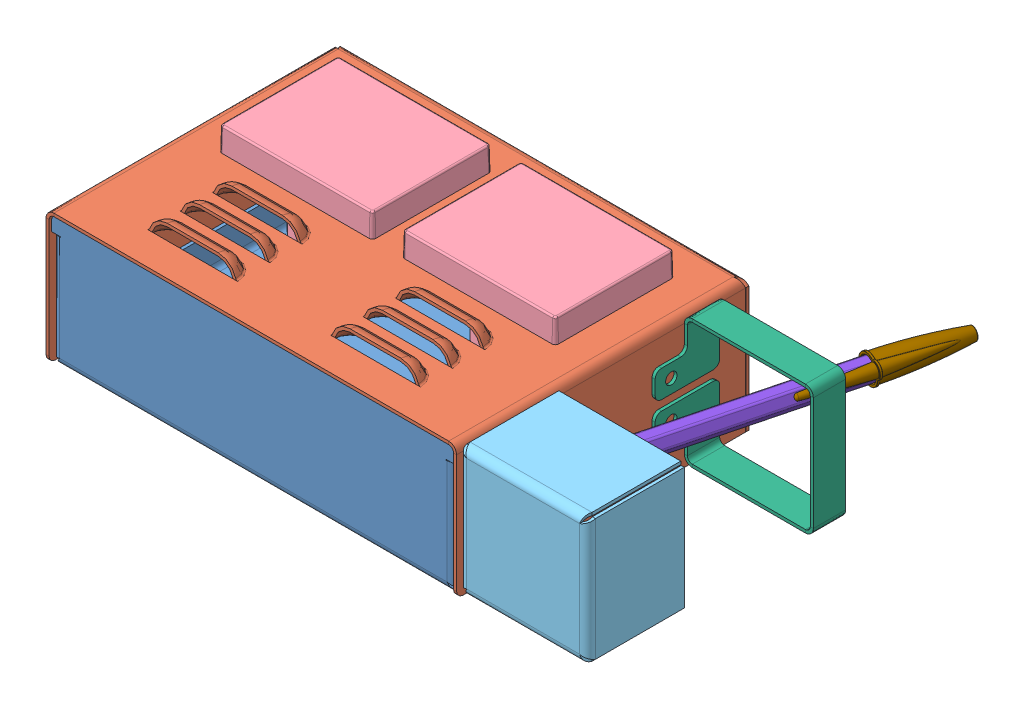
SolidWorks assembly L-Shape Assembly, configuration Default. Lengths in mm.
Overall size (225.75 61.58 154.1).
20 component instances, 13 part files, 25 mates.
Components (placement in the parent):
- Base-1: Base [Default] at origin size (158.76 50.8 112.83)
- Cover-1: Cover [Default] at (-80.8482 51.054 0.762) size (161.99 58.27 115.07)
- S-632-1 ZI-10: S-632-1 ZI [PEM S-632-1 ZI--N] at (-78.1558 28.575 -8.255) x (0 -1 0) z (0 0 1) size (7.11 2.74 7.11)
- S-632-1 ZI-11: S-632-1 ZI [PEM S-632-1 ZI--N] at (-78.1558 8.255 -20.955) x (0 -1 0) z (0 0 1) size (7.11 2.74 7.11)
- S-632-1 ZI-13: S-632-1 ZI [PEM S-632-1 ZI--N] at (-78.1558 8.255 -107.1118) x (0 -1 0) z (0 0 1) size (7.11 2.74 7.11)
- S-632-1 ZI-1: S-632-1 ZI [PEM S-440-1 ZI--N] at (78.1558 28.575 -8.255) x (0 1 0) z (0 0 1) size (6.35 2.74 6.35)
- S-632-1 ZI-4: S-632-1 ZI [PEM S-440-1 ZI--N] at (78.1558 8.255 -20.955) x (0 1 0) z (0 0 1) size (6.35 2.74 6.35)
- S-632-1 ZI-5: S-632-1 ZI [PEM S-440-1 ZI--N] at (78.1558 8.255 -107.1118) x (0 1 0) z (0 0 1) size (6.35 2.74 6.35)
- Jameco 316603-1: Jameco 316603 [Default] at (-35.9913 52.2732 -76.1931) x (1 0 0) z (0 1 0) size (60.5 47 37.3)
- Jameco 316603-2: Jameco 316603 [Default] at (35.9913 52.2732 -76.1931) x (1 0 0) z (0 1 0) size (60.5 47 37.3)
- Pencil Bottom-1: Pencil Bottom [Default] at (131.6482 52.2732 -1.2192) x (-1 0 0) z (0 0 1) size (50.8 50.8 50.8)
- Pencil Top-1: Pencil Top [Default] at (130.429 52.2732 -88.9) x (0 -1 0) z (1 0 0) size (50.8 25.4 50.8)
- BIC Pen Assembly Blue-1: BIC Pen Assembly Blue [Default] at (121.0447 61.6791 -89.1579) x (0.264397 0.013512 -0.964319) z (0.557576 0.813709 0.164278) size (148.8 15.39 16.22)
  - Nib-1: Nib [Default] at (57.1345 -8.7544 -20.0258) x (1 0 0) z (0 0.001361 0.999999) size (15.6 3.6 3.6)
  - Body-1: Body [Default] at (49.2214 -8.7544 -20.0258) size (134 7.6 8.57)
  - Pen Cap (Blue)-1: Pen Cap (Blue) [Default] at (28.2214 -8.7544 -20.0258) x (-1 0 0) z (0 0.890697 0.454597) size (60 12.7 10.8)
  - Nib Shroud-1: Nib Shroud [Default] at (54.7214 -8.7544 -20.0258) x (1 0 0) z (0 -0.048991 0.998799) size (14.5 5.4 5.4)
  - Nib Roller Ball-1: Nib Roller Ball [Default] at (57.1345 -8.7544 -20.0258) size (1.59 1.59 1.59)
  - End Cap (Blue)-1: End Cap (Blue) [Default] at (-79.2786 -8.7544 -20.0258) size (7.3 7.4 7.4)
  - Ink Tube-Vessel (Blue)-1: Ink Tube-Vessel (Blue) [Default] at (48.0214 -8.7544 -20.0258) size (120 2.96 2.96)
Mates (geometry in assembly coordinates):
- Distance4: distance = 0.254 mm anti-aligned: plane of Base-1; plane of Cover-1 through (207.2276 51.054 0.762) normal (0 -1 0)
- Distance6: distance = 0.762 mm aligned: plane of Base-1; plane of Cover-1
- Concentric71: concentric aligned: cylinder of Base-1 through (-79.375 8.255 -20.955) axis (1 0 0) radius 2.3876; cylinder of S-632-1 ZI-4 through (78.1558 8.255 -20.955) axis (1 0 0) radius 3.175
- Coincident141: coincident anti-aligned: plane of Base-1 through (78.1558 1.2192 -15.24) normal (-1 0 0); plane of S-632-1 ZI-4 through (78.1558 10.1276 -20.955) normal (1 0 0)
- Concentric81: concentric aligned: cylinder of Base-1 through (-79.375 8.255 -107.1118) axis (1 0 0) radius 2.3876; cylinder of S-632-1 ZI-5 through (78.1558 8.255 -107.1118) axis (1 0 0) radius 3.175
- Coincident151: coincident anti-aligned: plane of Base-1 through (78.1558 1.2192 -15.24) normal (-1 0 0); plane of S-632-1 ZI-5 through (78.1558 10.1276 -107.1118) normal (1 0 0)
- Concentric831: concentric aligned: cylinder of Base-1 through (-79.375 28.575 -8.255) axis (1 0 0) radius 2.3876; cylinder of S-632-1 ZI-1 through (78.1558 28.575 -8.255) axis (1 0 0) radius 3.175
- Coincident1531: coincident anti-aligned: plane of S-632-1 ZI-1 through (78.1558 30.4476 -8.255) normal (1 0 0); plane of Base-1 through (78.1558 3.1242 -1.2192) normal (-1 0 0)
- Distance7: distance = 0.254 mm anti-aligned: plane of Cover-1 through (-79.629 51.054 -111.1758) normal (1 0 0); plane of Base-1 through (-79.375 13.97 -15.24) normal (-1 0 0)
- Concentric83421: concentric anti-aligned: cylinder of Base-1 through (-79.375 28.575 -8.255) axis (1 0 0) radius 2.3876; cylinder of S-632-1 ZI-10 through (-78.1558 28.575 -8.255) axis (-1 0 0) radius 3.556
- Coincident153621: coincident anti-aligned: plane of Base-1 through (-78.1558 3.1242 -13.97) normal (1 0 0); plane of S-632-1 ZI-10 through (-78.1558 26.423 -8.255) normal (-1 0 0)
- Concentric83431: concentric anti-aligned: cylinder of Base-1 through (-79.375 8.255 -20.955) axis (1 0 0) radius 2.3876; cylinder of S-632-1 ZI-11 through (-78.1558 8.255 -20.955) axis (-1 0 0) radius 3.556
- Coincident153631: coincident anti-aligned: plane of Base-1 through (-78.1558 13.97 -15.24) normal (1 0 0); plane of S-632-1 ZI-11 through (-78.1558 6.103 -20.955) normal (-1 0 0)
- Concentric83451: concentric anti-aligned: cylinder of Base-1 through (-79.375 8.255 -107.1118) axis (1 0 0) radius 2.3876; cylinder of S-632-1 ZI-13 through (-78.1558 8.255 -107.1118) axis (-1 0 0) radius 3.556
- Coincident153651: coincident anti-aligned: plane of Base-1 through (-78.1558 13.97 -15.24) normal (1 0 0); plane of S-632-1 ZI-13 through (-78.1558 6.103 -107.1118) normal (-1 0 0)
- Concentric83453: concentric aligned: cylinder of Cover-1 through (35.9913 0 -76.1931) axis (0 1 0) radius 19.25; cylinder of Jameco 316603-2 through (35.9913 28.2732 -76.1931) axis (0 1 0) radius 19
- Coincident153652: coincident anti-aligned: plane of Cover-1 through (207.2276 52.2732 0.762) normal (0 1 0); plane of Jameco 316603-2 through (35.9913 52.2732 -76.1931) normal (0 -1 0)
- Coincident153653: coincident anti-aligned: plane of Cover-1 through (207.2276 52.2732 0.762) normal (0 1 0); plane of Jameco 316603-1 through (-35.9913 52.2732 -76.1931) normal (0 -1 0)
- Concentric83454: concentric aligned: cylinder of Cover-1 through (-35.9913 0 -76.1931) axis (0 1 0) radius 19.25; cylinder of Jameco 316603-1 through (-35.9913 28.2732 -76.1931) axis (0 1 0) radius 19
- Coincident153654: coincident anti-aligned: plane of Cover-1 through (80.8482 51.054 0.762) normal (1 0 0); plane of Pencil Bottom-1 through (80.8482 52.2732 -1.2192) normal (-1 0 0)
- Coincident153655: coincident aligned: plane of Cover-1 through (207.2276 52.2732 0.762) normal (0 1 0); plane of Pencil Bottom-1 through (131.6482 52.2732 -1.2192) normal (0 1 0)
- Coincident153656: coincident aligned: plane of Base-1; plane of Pencil Bottom-1
- Coincident153657: coincident anti-aligned: plane of Cover-1 through (80.8482 51.054 0.762) normal (1 0 0); plane of Pencil Top-1 through (80.8482 52.2732 -88.9) normal (-1 0 0)
- Distance8: distance = 12.7 mm aligned: plane of Cover-1 through (207.2276 51.054 -114.3) normal (0 0 -1); plane of Pencil Top-1 through (80.8482 52.2732 -101.6) normal (0 0 -1)
- Coincident153659: coincident aligned: plane of Cover-1 through (207.2276 52.2732 0.762) normal (0 1 0); plane of Pencil Top-1 through (130.429 52.2732 -88.9) normal (0 1 0)
